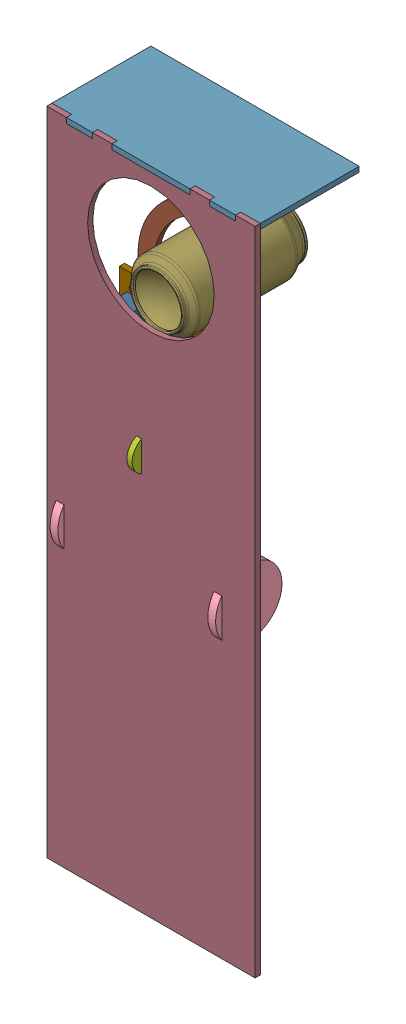
SolidWorks assembly Assem2, configuration Default. Lengths in mm.
Overall size (203.2 635 144.54).
19 component instances, 14 part files, 32 mates.
Components (placement in the parent):
- bottomframe-1: bottomframe [Default] at (-19.6615 177.1928 124.5284) size (127 177.8 5.08)
- sidepiece-1: sidepiece [Default] at (102.2585 -0.6072 91.5084) x (0 -1 0) z (0 0 1) size (177.8 5.08 38.1)
- continousserov-1: continousserov [Default] at (116.9651 82.7302 124.5284) x (0 1 0) z (0 0 -1) size (55.5 41.69 19.86)
- wheel-1: wheel [Default] at (120.7751 45.3858 114.6288) x (0 -0.995495 -0.094818) z (1 0 0) size (64.69 64.69 7.62)
- sidepiece-2: sidepiece [Default] at (-19.6615 -0.6072 91.5084) x (0 -1 0) z (0 0 1) size (177.8 5.08 38.1)
- continousserov-2: continousserov [Default] at (-29.2881 82.7302 104.7164) x (0 1 0) z (0 0 1) size (55.5 41.69 19.86)
- wheel-2: wheel [Default] at (-33.0981 45.3858 114.6161) x (0 -0.829213 -0.558933) z (-1 0 0) size (64.69 64.69 7.62)
- backpiece-1: backpiece [Default] at (43.8385 1.9328 110.5584) size (127 5.08 38.1)
- flexsensor-1: flexsensor [Default] at (56.1567 376.4506 93.6368) x (0.943111 -0.332477 0) z (-0.332477 -0.943111 0) size (73.96 6.58 0.5)
- slider-1: slider [Default] at (46.3785 142.9028 137.2284) x (0 1 0) z (-1 0 0) size (33.02 25.67 5.08)
- front-1: front [Default] at (43.8385 174.6528 110.5584) size (127 5.08 38.1)
- Assem1-2: Assem1 [Default] at (5.4063 304.8496 205.6745) x (-1 0 0) z (0 -1 0) size (143.04 120.89 365.21)
  - clawbase1.0-2: clawbase1.0 [Default] at (-82.8822 109.086 56.4175) size (127 5.08 365.21)
  - standardservo-2: standardservo [Default] at (-2.3642 87.6865 114.2253) x (0 0 1) z (0 1 0) size (52.79 19.81 38.7)
  - claw1.0-2: claw1.0 [Default] at (38.7855 126.3834 129.422) x (0.95655 0 0.291569) z (0 1 0) size (118.63 96.83 5.08)
  - coke CAN-2: coke CAN [FOR DRINK] at (-50.5151 130.1366 28.3682) size (66.14 120.89 66.14)
- wallassem-1: wallassem [Default] at (623.1056 59.6945 526.3456) x (0 1 0) z (-1 0 0) size (635 101.6 203.2)
  - base-1: base [Default] at (15.3816 385.4027 567.6731) size (635 5.08 203.2)
  - walledge-1: walledge [Default] at (332.8816 436.2027 567.6731) x (0 0 1) z (-1 0 0) size (203.2 101.6 5.08)
Mates (geometry in assembly coordinates):
- Coincident4: coincident aligned: plane of bottomframe-1 through (107.3385 177.1928 129.6084) normal (1 0 0); plane of sidepiece-1 through (107.3385 -0.6072 91.5084) normal (1 0 0)
- Coincident5: coincident anti-aligned: plane of bottomframe-1 through (107.3385 10.8228 155.5115) normal (0 1 0); plane of sidepiece-1 through (89.7504 10.8228 124.5284) normal (0 -1 0)
- Coincident6: coincident aligned: plane of bottomframe-1 through (-19.6615 177.1928 129.6084) normal (0 0 1); plane of sidepiece-1 through (107.3385 -0.6072 129.6084) normal (0 0 1)
- Coincident8: coincident anti-aligned: plane of sidepiece-1 through (57.1036 75.5293 124.5284) normal (0 0 -1); plane of continousserov-1 through (116.9651 82.7302 124.5284) normal (0 0 1)
- Coincident9: coincident anti-aligned: plane of sidepiece-1 through (107.3385 -0.6072 91.5084) normal (1 0 0); plane of continousserov-1 through (107.3385 27.2312 151.9767) normal (-1 0 0)
- Coincident12: coincident anti-aligned: plane of sidepiece-1 through (57.1036 34.9528 104.7164) normal (0 1 0); plane of continousserov-1 through (116.9651 34.9528 151.9767) normal (0 -1 0)
- Coincident14: coincident anti-aligned: plane of continousserov-1 through (116.9651 82.7302 104.6656) normal (1 0 0); plane of wheel-1 through (116.9651 45.3858 114.6288) normal (-1 0 0)
- Concentric2: concentric anti-aligned: cylinder of continousserov-1 through (122.6928 45.3858 114.6288) axis (-1 0 0) radius 2.9655; cylinder of wheel-1 through (109.2421 45.3858 114.6288) axis (1 0 0) radius 2.7305
- Coincident19: coincident aligned: plane of bottomframe-1 through (-19.6615 177.1928 129.6084) normal (-1 0 0); plane of sidepiece-2 through (-19.6615 -0.6072 91.5084) normal (-1 0 0)
- Coincident20: coincident anti-aligned: plane of bottomframe-1 through (-14.5815 10.8228 155.5115) normal (0 1 0); plane of sidepiece-2 through (-32.1696 10.8228 124.5284) normal (0 -1 0)
- Coincident21: coincident aligned: plane of bottomframe-1 through (-19.6615 177.1928 129.6084) normal (0 0 1); plane of sidepiece-2 through (-14.5815 -0.6072 129.6084) normal (0 0 1)
- Coincident22: coincident anti-aligned: plane of sidepiece-2 through (-19.6615 -0.6072 91.5084) normal (-1 0 0); plane of continousserov-2 through (-19.6615 27.2312 77.2682) normal (1 0 0)
- Coincident23: coincident anti-aligned: plane of sidepiece-2 through (-64.8164 75.5293 104.7164) normal (0 0 1); plane of continousserov-2 through (-29.2881 82.7302 104.7164) normal (0 0 -1)
- Coincident24: coincident anti-aligned: plane of sidepiece-2 through (-64.8164 34.9528 104.7164) normal (0 1 0); plane of continousserov-2 through (-29.2881 34.9528 77.2682) normal (0 -1 0)
- Coincident25: coincident anti-aligned: plane of continousserov-2 through (-29.2881 82.7302 124.5792) normal (-1 0 0); plane of wheel-2 through (-29.2881 45.3858 114.6161) normal (1 0 0)
- Concentric3: concentric anti-aligned: cylinder of continousserov-2 through (-35.0158 45.3858 114.6161) axis (1 0 0) radius 2.9655; cylinder of wheel-2 through (-21.5651 45.3858 114.6161) axis (-1 0 0) radius 2.7305
- Coincident26: coincident aligned: plane of sidepiece-1 through (107.3385 -0.6072 91.5084) normal (0 -1 0); plane of backpiece-1 through (43.8385 -0.6072 110.5584) normal (0 -1 0)
- Coincident27: coincident anti-aligned: plane of sidepiece-1 through (121.0168 -0.6072 114.3684) normal (0 0 -1); plane of backpiece-1 through (107.3385 -0.6072 114.3684) normal (0 0 1)
- Coincident28: coincident aligned: plane of sidepiece-1 through (107.3385 -0.6072 91.5084) normal (1 0 0); plane of backpiece-1 through (107.3385 4.4728 129.6084) normal (1 0 0)
- Coincident46: coincident anti-aligned: plane of bottomframe-1 through (-19.6615 177.1928 129.6084) normal (0 0 1); plane of slider-1 through (60.0568 136.5528 129.6084) normal (0 0 -1)
- Coincident47: coincident anti-aligned: plane of bottomframe-1 through (41.2985 126.3928 113.1692) normal (0 1 0); plane of slider-1 through (41.2985 126.3928 124.5284) normal (0 -1 0)
- Coincident48: coincident anti-aligned: plane of bottomframe-1 through (41.2985 136.5528 113.1692) normal (1 0 0); plane of slider-1 through (41.2985 142.9028 133.6612) normal (-1 0 0)
- Coincident52: coincident aligned: plane of bottomframe-1 through (-19.6615 177.1928 129.6084) normal (0 1 0); plane of front-1 through (43.8385 177.1928 110.5584) normal (0 1 0)
- Coincident53: coincident aligned: plane of sidepiece-2 through (-19.6615 -0.6072 91.5084) normal (-1 0 0); plane of front-1 through (-19.6615 177.1928 129.6084) normal (-1 0 0)
- Coincident54: coincident anti-aligned: plane of sidepiece-2 through (-33.3398 177.1928 101.6684) normal (0 0 1); plane of front-1 through (-19.6615 172.1128 101.6684) normal (0 0 -1)
- Coincident61: coincident anti-aligned: plane of backpiece-1 through (-14.5815 -117.5576 96.5884) normal (0 0 -1); plane of Assem1-2/clawbase1.0-2 through (88.2885 248.4321 96.5884) normal (0 0 1)
- Coincident62: coincident aligned: plane of sidepiece-1 through (107.3385 -0.6072 91.5084) normal (1 0 0); plane of Assem1-2/clawbase1.0-2 through (107.3385 177.1928 91.5084) normal (1 0 0)
- Coincident63: coincident aligned: plane of backpiece-1 through (43.8385 -0.6072 110.5584) normal (0 -1 0); plane of Assem1-2/clawbase1.0-2 through (107.3385 -0.6072 91.5084) normal (0 -1 0)
- Coincident65: coincident anti-aligned: plane of flexsensor-1 through (23.509 387.4347 94.3861) normal (-0.332477 -0.943111 0); plane of Assem1-2/clawbase1.0-2 through (107.3385 357.8822 91.5084) normal (0.332477 0.943111 0)
- Coincident68: coincident anti-aligned: circle of Assem1-2/coke CAN-2; plane of wallassem-1/base-1 through (55.4326 75.0761 135.8629) normal (0 0 -1)
- Parallel3: parallel aligned: plane of Assem1-2/clawbase1.0-2 through (107.3385 177.1928 91.5084) normal (1 0 0); plane of wallassem-1/base-1 through (157.0326 392.5761 135.8629) normal (1 0 0)
- Parallel4: parallel: plane of sidepiece-2 through (-19.6615 -0.6072 91.5084) normal (-1 0 0); line of wallassem-1/base-1 through (-46.1674 -242.4239 135.8629) axis (0 1 0)
